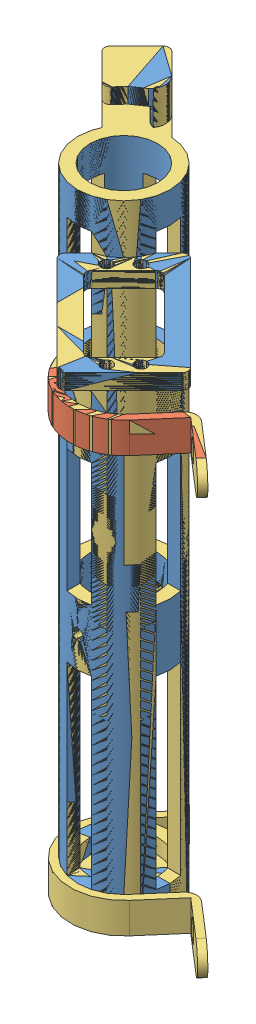
SolidWorks assembly Tube_and_bracket, configuration Default. Lengths in mm.
Overall size (126.14 274.32 117.72).
4 component instances, 3 part files, 7 mates.
Components (placement in the parent):
- Tube-1: Tube [Default] at origin size (98.43 274.32 103.82) (hidden)
- Tube_Bracket-1: Tube_Bracket [Default] at (14.6284 171.45 -11.0849) x (-0.756941 0 -0.653483) z (0 1 0) size (98.1 43 12.7) (hidden)
- Tube_Bracket-2: Tube_Bracket [Default] at (14.6284 0 -11.0849) x (-0.756941 0 -0.653483) z (0 1 0) size (98.1 43 12.7) (hidden)
- T&B1-1: T&B1 [Default] at (14.6284 171.45 -11.0849) x (-0.756941 0 -0.653483) z (0 1 0) size (127.11 45.78 274.32)
Mates (geometry in assembly coordinates):
- Concentric1: concentric anti-aligned: circle of Tube-1; circle of Tube_Bracket-1
- Distance1: distance = 6.35 mm aligned: plane of Tube_Bracket-1 through (14.6284 171.45 -11.0849) normal (0 -1 0); plane of Tube-1 through (0 165.1 -19.05) normal (0 -1 0)
- Concentric2: concentric anti-aligned: cylinder of Tube-1; cylinder of Tube_Bracket-2 through (0 0 0) axis (0 -1 0) radius 19.05
- InPlace1: in place: plane of ? through (14.6284 171.45 -11.0849) normal (0 1 0); plane of ? through (14.6284 171.45 -11.0849) normal (0 1 0); moOrthogonalPlaneRef_w of ? through (14.6284 171.45 -11.0849) normal (0 1 0); plane of ? through (14.6284 171.45 -11.0849) normal (-0.653483 0 0.756941); plane of ? through (14.6284 171.45 -11.0849) normal (0 1 0); plane of ? through (14.6284 171.45 -11.0849) normal (-0.756941 0 -0.653483); plane of ? through (14.6284 171.45 -11.0849) normal (0 1 0); unknown of ?
- Coincident1: coincident aligned: plane of ?; plane of ?
- Coincident2: coincident aligned: moOrthogonalPlaneRef_w of Tube_Bracket-1; plane of Part3^Tube_and_bracket-1 through (14.6284 171.45 -11.0849) normal (-0.653483 0 0.756941)
- Coincident3: coincident anti-aligned: moOrthogonalPlaneRef_w of Tube_Bracket-1; plane of Part3^Tube_and_bracket-1 through (14.6284 171.45 -11.0849) normal (-0.756941 0 -0.653483)
